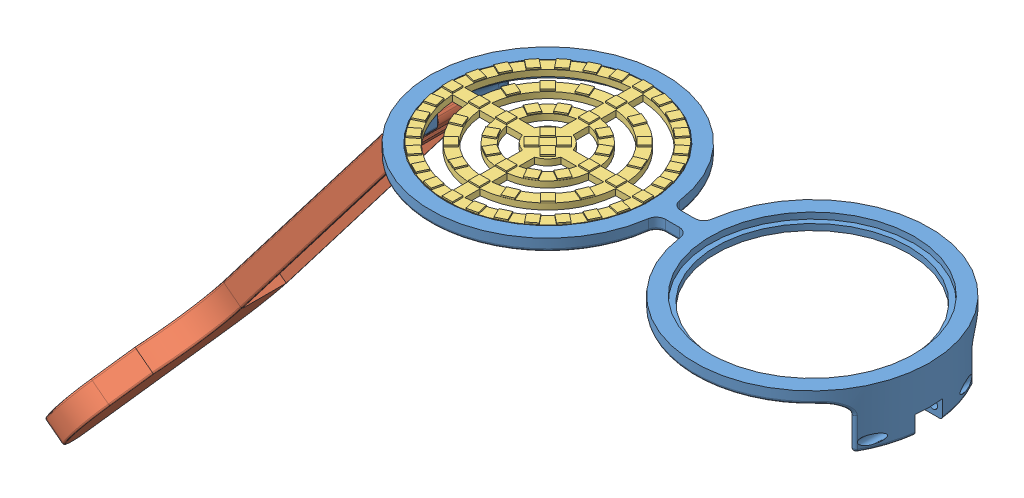
SolidWorks assembly REZZGLASSES-V1, configuration Default. Lengths in mm.
Overall size (255.53 132.33 76.5).
3 component instances, 3 part files, 4 mates.
Components (placement in the parent):
- FrameTest2-1: FrameTest2 [Default] at (57.4837 100.9347 122.4531) size (162.81 18.56 76.5)
- FrameSideTest1-1: FrameSideTest1 [Default] at (-15.4707 95.1932 122.4531) x (-0.793641 0.608387 0) z (-0.608387 -0.793641 0) size (7.66 43.77 156.34)
- SizingTest_V2-1: SizingTest_V2 [Default] at (14.3278 102.9347 122.4531) x (-1 0 0.00053) z (0.00053 0 1) size (66 2.5 66)
Mates (geometry in assembly coordinates):
- Concentric1: concentric anti-aligned: cylinder of FrameTest2-1 through (-20.5472 95.9347 92.4531) axis (0 0 1) radius 1.75; cylinder of FrameSideTest1-1 through (-20.5472 95.9347 158.2233) axis (0 0 -1) radius 1.75
- Coincident1: coincident: line of FrameTest2-1 through (-23.6566 98.9347 126.9531) axis (0 -1 0); plane of FrameSideTest1-1 through (-27.5099 80.7209 126.9531) normal (0 0 1)
- Coincident2: coincident anti-aligned: plane of FrameTest2-1 through (100.6395 100.9347 122.4531) normal (0 1 0); plane of SizingTest_V2-1 through (14.3278 100.9347 122.4531) normal (0 -1 0)
- Concentric2: concentric anti-aligned: cylinder of FrameTest2-1 through (14.3278 102.9347 122.4531) axis (0 -1 0) radius 33.25; cylinder of SizingTest_V2-1 through (14.3278 100.9347 122.4531) axis (0 1 0) radius 33
